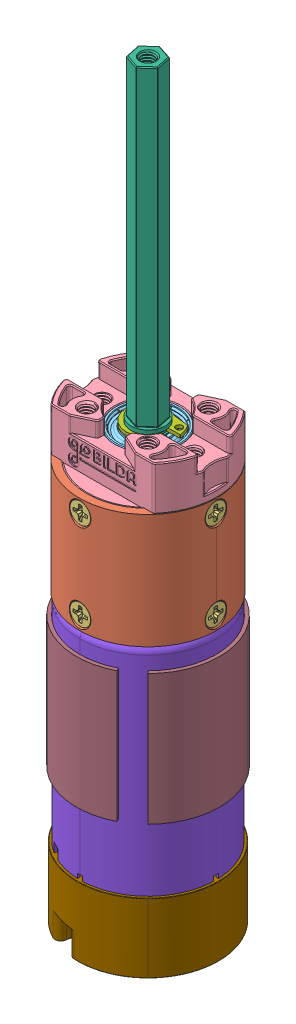
SolidWorks assembly Rex shaft 435rpm motor LONG, configuration Default. Lengths in mm.
Overall size (52.29 196.05 52.29).
30 component instances, 15 part files, 0 mates.
Components (placement in the parent):
- 5204-8002-0014 assembly.STEP-1: 5204-8002-0014 assembly.STEP [Default] at origin size (52.29 196.05 52.29)
  - 5104-8002-0014 Simple.STEP-1: 5104-8002-0014 Simple.STEP [Default] at (21.5499 39.1 -25.8711) size (36 121.1 35.97)
    - 5103 Gearbox Base.STEP-1: 5103 Gearbox Base.STEP [Default] at (-58.7206 21.0354 14.7927) size (31.91 5.69 31.91)
    - 5103 Gearbox Barrel (2 stage, simple)_Gear Blank.STEP-1: 5103 Gearbox Barrel (2 stage, simple)_Gear Blank.STEP [Default] at (-58.7206 64.0354 14.7927) x (1 0 0) z (0 -1 0) size (35.97 35.97 30)
    - 5103 Gearbox Barrel Screw (M3 x 8mm length Flat Head)_92010A118.STEP-1: 5103 Gearbox Barrel Screw (M3 x 8mm length Flat Head)_92010A118.STEP [Default] at (-58.7206 24.5354 30.8757) x (0.002439 -0.999997 0) z (0 0 1) size (5.46 5.46 8)
    - 5103 Gearbox Barrel Screw (M3 x 8mm length Flat Head)_92010A118.STEP-2: 5103 Gearbox Barrel Screw (M3 x 8mm length Flat Head)_92010A118.STEP [Default] at (-58.7206 47.5354 30.8757) x (-0.002439 -0.999997 0) z (0 0 1) size (5.46 5.46 8)
    - 5103 Gearbox Barrel Screw (M3 x 8mm length Flat Head)_92010A118.STEP-3: 5103 Gearbox Barrel Screw (M3 x 8mm length Flat Head)_92010A118.STEP [Default] at (-42.6376 24.5354 14.7927) x (0 -0.999997 -0.002439) z (1 0 0) size (5.46 5.46 8)
    - 5103 Gearbox Barrel Screw (M3 x 8mm length Flat Head)_92010A118.STEP-4: 5103 Gearbox Barrel Screw (M3 x 8mm length Flat Head)_92010A118.STEP [Default] at (-58.7206 24.5354 -1.2903) x (-0.002439 -0.999997 0) z (0 0 -1) size (5.46 5.46 8)
    - 5103 Gearbox Barrel Screw (M3 x 8mm length Flat Head)_92010A118.STEP-5: 5103 Gearbox Barrel Screw (M3 x 8mm length Flat Head)_92010A118.STEP [Default] at (-74.8037 24.5354 14.7927) x (0 -0.999997 0.002439) z (-1 0 0) size (5.46 5.46 8)
    - 5103 Gearbox Barrel Screw (M3 x 8mm length Flat Head)_92010A118.STEP-6: 5103 Gearbox Barrel Screw (M3 x 8mm length Flat Head)_92010A118.STEP [Default] at (-42.6376 47.5354 14.7927) x (0 -0.999997 0.002439) z (1 0 0) size (5.46 5.46 8)
    - 5103 Gearbox Barrel Screw (M3 x 8mm length Flat Head)_92010A118.STEP-7: 5103 Gearbox Barrel Screw (M3 x 8mm length Flat Head)_92010A118.STEP [Default] at (-58.7206 47.5354 -1.2903) x (0.002439 -0.999997 0) z (0 0 -1) size (5.46 5.46 8)
    - 5103 Gearbox Barrel Screw (M3 x 8mm length Flat Head)_92010A118.STEP-8: 5103 Gearbox Barrel Screw (M3 x 8mm length Flat Head)_92010A118.STEP [Default] at (-74.8037 47.5354 14.7927) x (0 -0.999997 -0.002439) z (-1 0 0) size (5.46 5.46 8)
    - 5103 Gearbox Face.STEP-1: 5103 Gearbox Face.STEP [Default] at (-58.7206 45.5354 14.7927) size (36 17.1 31.91)
    - 5103 Gearbox Bearing.STEP-1: 5103 Gearbox Bearing.STEP [Default] at (-58.7206 53.6354 14.7927) size (17 5 17)
    - 5103 Gearbox Bearing.STEP-2: 5103 Gearbox Bearing.STEP [Default] at (-58.7206 45.5354 14.7927) size (17 5 17)
    - 5103 Gearbox Shaft (79.5mm Length, Simple).STEP-1: 5103 Gearbox Shaft (79.5mm Length, Simple).STEP [Default] at (-58.7206 42.1754 14.7927) x (0.74423 0 -0.667923) z (0.667923 0 0.74423) size (8.97 96.6 8.97)
    - 5103 Gearbox Snap Ring.STEP-1: 5103 Gearbox Snap Ring.STEP [Default] at (-58.7206 58.7104 14.7927) x (0 1 0) z (0 0 1) size (0.85 13.06 10.66)
  - 5000-0002-0001 body.step-1: 5000-0002-0001 body.step [Default] at (-37.1707 3.4854 -11.0784) size (35.61 61.8 35.61)
  - 5000-0001-0001 encoder cap.STEP-1: 5000-0001-0001 encoder cap.STEP [Default] at (-37.1707 -14.6146 -11.0784) x (0.707107 0 -0.707107) z (0 -1 0) size (36.9 36.9 18.3)
  - 5000-0001-0001 encoder cap screw_90190A075.STEP-1: 5000-0001-0001 encoder cap screw_90190A075.STEP [Default] at (-33.0775 -8.1646 -26.1474) x (0.882398 0 0.470504) z (0 -1 0) size (3.33 3.33 7.86)
  - 5000-0001-0001 encoder pin housing.STEP-1: 5000-0001-0001 encoder pin housing.STEP [Default] at (-44.0085 -0.9746 -21.9467) x (0.707107 0 -0.707107) z (-0.707107 0 -0.707107) size (12.3 7.19 6.3)
  - 5000-0001-0001 encoder pins_MalePinHeader_1X2.STEP-1: 5000-0001-0001 encoder pins_MalePinHeader_1X2.STEP [Default] at (-43.4569 1.2544 -23.1912) x (0.707107 0 -0.707107) z (0 -1 0) size (3.18 0.64 4.27)
  - 5000-0001-0001 motor shield.STEP-1: 5000-0001-0001 motor shield.STEP [Default] at (-37.1707 54.6354 -11.0784) x (0.808104 0 -0.58904) z (0 -1 0) size (37.5 37.27 34.15)
  - 5000-0001-0001 encoder cap screw_90190A075.STEP-2: 5000-0001-0001 encoder cap screw_90190A075.STEP [Default] at (-41.264 -8.1646 3.9905) x (0.882398 0 0.470504) z (0 -1 0) size (3.33 3.33 7.86)
  - 5000-0001-0001 encoder pins_MalePinHeader_1X2.STEP-2: 5000-0001-0001 encoder pins_MalePinHeader_1X2.STEP [Default] at (-47.049 1.2544 -19.5991) x (0.707107 0 -0.707107) z (0 -1 0) size (3.18 0.64 4.27)
  - 5000-0002-0117 motor shaft.STEP-1: 5000-0002-0117 motor shaft.STEP [Default] at (-37.1707 59.4854 -11.0784) size (3.26 12.45 3.14)
  - 5103 Gearbox Base Mounting Screw M3 x 5mm length SHCS)_91290A110.STEP-1: 5103 Gearbox Base Mounting Screw M3 x 5mm length SHCS)_91290A110.STEP [Default] at (-46.0096 57.2554 -2.2396) x (0.056382 0 0.998409) z (0 -1 0) size (5.5 5.5 8.01)
  - 5103 Gearbox Base Mounting Screw M3 x 5mm length SHCS)_91290A110.STEP-2: 5103 Gearbox Base Mounting Screw M3 x 5mm length SHCS)_91290A110.STEP [Default] at (-28.3319 57.2554 -2.2396) x (0.998409 0 -0.056382) z (0 -1 0) size (5.5 5.5 8.01)
  - 5103 Gearbox Base Mounting Screw M3 x 5mm length SHCS)_91290A110.STEP-3: 5103 Gearbox Base Mounting Screw M3 x 5mm length SHCS)_91290A110.STEP [Default] at (-28.3319 57.2554 -19.9173) x (-0.056382 0 -0.998409) z (0 -1 0) size (5.5 5.5 8.01)
  - 5103 Gearbox Base Mounting Screw M3 x 5mm length SHCS)_91290A110.STEP-4: 5103 Gearbox Base Mounting Screw M3 x 5mm length SHCS)_91290A110.STEP [Default] at (-46.0096 57.2554 -19.9173) x (-0.998409 0 0.056382) z (0 -1 0) size (5.5 5.5 8.01)
